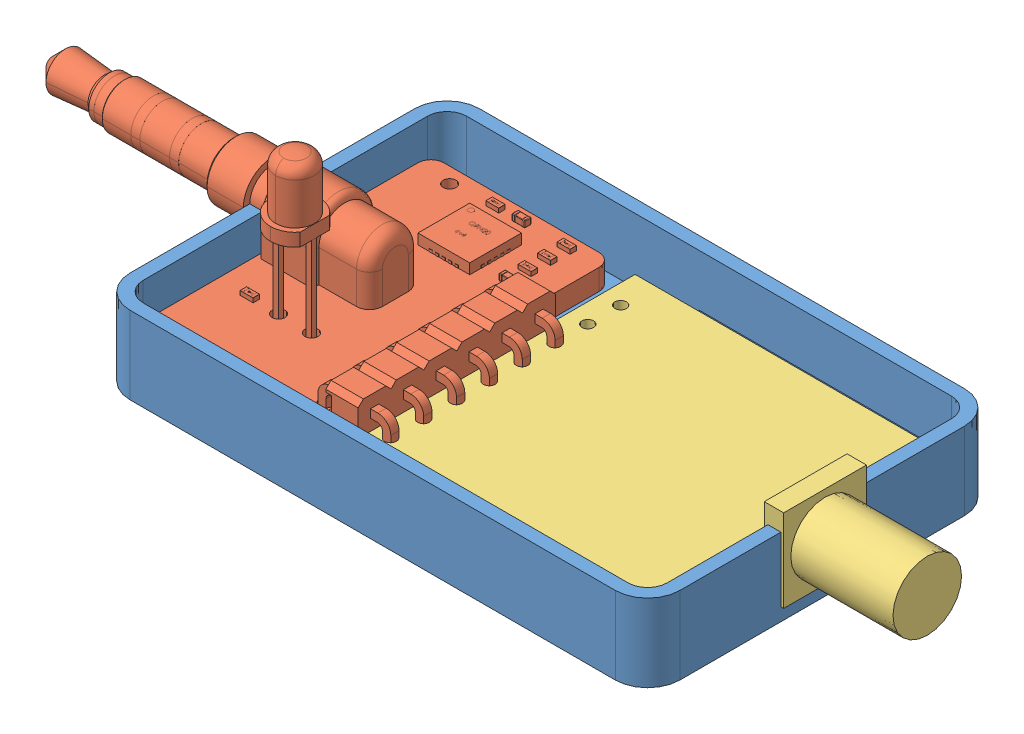
SolidWorks assembly Assembly, configuration Default. Lengths in mm.
Overall size (67.62 15.23 27).
3 component instances, 3 part files, 2 mates.
Components (placement in the parent):
- Tray-1: Tray [Default] at origin size (42.5 6 27)
- x-IMU3-SA-GPS-1: x-IMU3-SA-GPS [Default] at (-39 3.5 10.9999) x (1 0 0) z (0 1 0) size (36.07 22 14.23)
- HAB-BO-M8Q3A-ASSY-1: HAB-BO-M8Q3A-ASSY [Default] at (7.965 2 0.431) size (33.4 6.4 22.5)
Mates (geometry in assembly coordinates):
- Coincident4: coincident: plane of Tray-1 through (0 1 0) normal (0 1 0); plane of HAB-BO-M8Q3A-ASSY-1 through (21.465 1 3.2) normal (0 -1 0)
- Coincident5: coincident: plane of Tray-1 through (14.85 1 3.2) normal (0 0 -1); plane of HAB-BO-M8Q3A-ASSY-1 through (21.465 7.4 3.2) normal (0 0 1)
